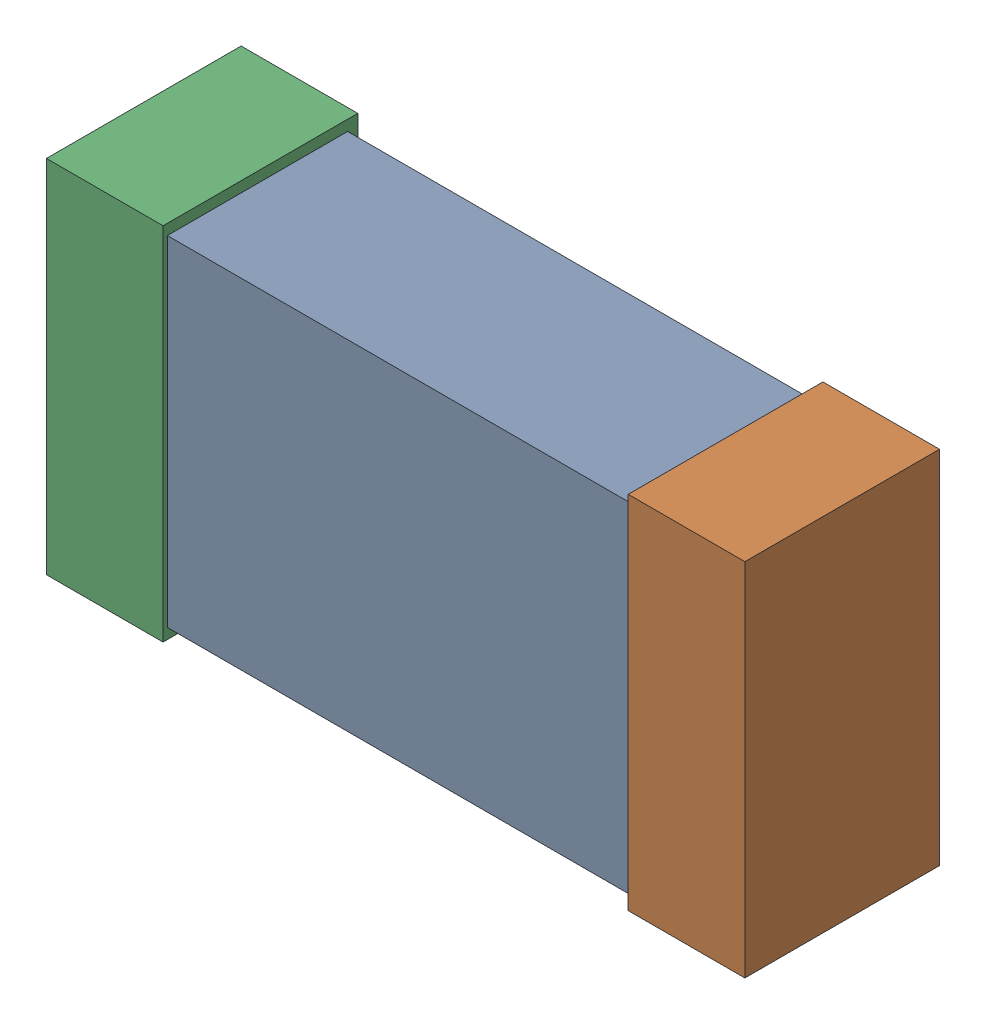
SolidWorks assembly C15, configuration Default. Lengths in mm.
Overall size (1.65 0.85 0.46).
6 component instances, 2 part files, 0 mates.
Components (placement in the parent):
- 432120720_9-1: 432120720_9 [Default] at (31.0957 15.3112 0.025) size (1.5 0.8 0.42)
  - Extruded (12)-1: Extruded (12) [Default] at origin size (1.5 0.8 0.42)
- 432120464_18-1: 432120464_18 [Default] at (31.7815 15.3112 0.001) size (0.28 0.85 0.46)
  - Extruded (11)-1: Extruded (11) [Default] at origin size (0.28 0.85 0.46)
- 432120464_19-1: 432120464_19 [Default] at (30.4099 15.3112 0.001) size (0.28 0.85 0.46)
  - Extruded (11)-1: Extruded (11) [Default] at origin size (0.28 0.85 0.46)
